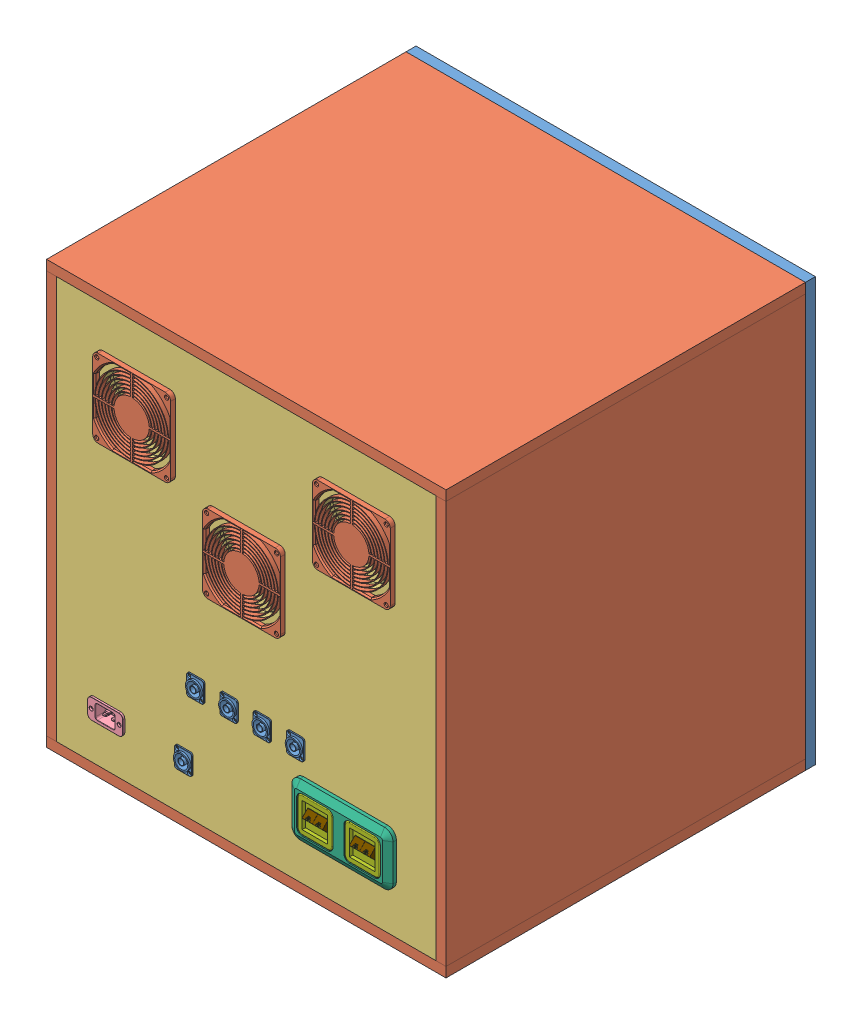
SolidWorks assembly Verlängerung, configuration Standard. Lengths in mm.
Overall size (600 635 570.02).
74 component instances, 21 part files, 63 mates.
Components (placement in the parent):
- Lochplatte-1: Lochplatte [Standard] at (-600 0 0) size (600 635 15)
- Platten-1: Platten [Standard] at (-600 620 555) x (1 0 0) z (0 1 0) size (600 540 15)
- Platten-2: Platten [Standard] at (-600 0 555) x (1 0 0) z (0 1 0) size (600 540 15)
- Platten-3: Platten [seite] at (-585 15 555) x (0 1 0) z (-1 0 0) size (605 540 15)
- Platten-4: Platten [seite] at (0 15 555) x (0 1 0) z (-1 0 0) size (605 540 15)
- Back-1: Back [Standard] at (-585 15 540) size (570 605 15)
- 17322-1: 17322 [Default] at (-509 87 555) size (53 30 30)
- Hohlwanddose-1: Hohlwanddose [Standard] at (-186 115 556) x (0 0 -1) z (1 0 0) size (60.7 71 71)
- Hohlwanddose-2: Hohlwanddose [Standard] at (-115 115 556) x (0 0 -1) z (1 0 0) size (60.7 71 71)
- Steckdose_2er-RJ45-1: Steckdose_2er-RJ45 [Standard] at (-243.8004 7.3351 555.8552) size (152 80 25.23)
  - Wandplatte-1: Wandplatte [2er] at (17.3004 67.6649 10.1448) size (152 80 11)
  - Steckdose-RJ45-1: Steckdose-RJ45 [Standard] at (177.7047 18.6812 -53.8826) x (0 -1 0) z (0 0 1) size (54 54 25.23)
    - Buchse-RJ45-1: Buchse-RJ45 [Standard] at (-88.9836 -48.9043 64.0274) size (54 54 6.5)
    - 65864-1: 65864 [Default] at (-88.8386 -41.2043 53.1274) size (17.49 15.42 25.23)
      - 65864_01-1: 65864_01 [Default] at origin size (9.69 0.75 13.83)
      - 65864_02-1: 65864_02 [Default] at origin size (9.44 0.68 13.83)
      - 65864_03-1: 65864_03 [Default] at origin size (9.69 0.61 13.84)
      - 65864_04-1: 65864_04 [Default] at origin size (9.44 0.54 13.83)
      - 65864_05-1: 65864_05 [Default] at origin size (9.69 0.54 13.82)
      - 65864_06-1: 65864_06 [Default] at origin size (9.44 0.6 13.83)
      - 65864_07-1: 65864_07 [Default] at origin size (9.69 0.68 13.83)
      - 65864_08-1: 65864_08 [Default] at origin size (9.44 0.75 13.83)
      - 65864_09-1: 65864_09 [Default] at origin size (17.11 15.1 23.65)
      - 65864_10-1: 65864_10 [Default] at origin size (6.36 10.31 6.36)
      - 65864_11-1: 65864_11 [Default] at origin size (17.49 15.42 25.23)
    - 65864-2: 65864 [Default] at (-88.8386 -56.6043 53.1274) size (17.49 15.42 25.23)
      - 65864_01-1: 65864_01 [Default] at origin size (9.69 0.75 13.83)
      - 65864_02-1: 65864_02 [Default] at origin size (9.44 0.68 13.83)
      - 65864_03-1: 65864_03 [Default] at origin size (9.69 0.61 13.84)
      - 65864_04-1: 65864_04 [Default] at origin size (9.44 0.54 13.83)
      - 65864_05-1: 65864_05 [Default] at origin size (9.69 0.54 13.82)
      - 65864_06-1: 65864_06 [Default] at origin size (9.44 0.6 13.83)
      - 65864_07-1: 65864_07 [Default] at origin size (9.69 0.68 13.83)
      - 65864_08-1: 65864_08 [Default] at origin size (9.44 0.75 13.83)
      - 65864_09-1: 65864_09 [Default] at origin size (17.11 15.1 23.65)
      - 65864_10-1: 65864_10 [Default] at origin size (6.36 10.31 6.36)
      - 65864_11-1: 65864_11 [Default] at origin size (17.49 15.42 25.23)
  - Steckdose-RJ45-2: Steckdose-RJ45 [Standard] at (106.7047 18.6812 -53.8826) x (0 -1 0) z (0 0 1) size (54 54 25.23)
    - Buchse-RJ45-1: Buchse-RJ45 [Standard] at (-88.9836 -48.9043 64.0274) size (54 54 6.5)
    - 65864-1: 65864 [Default] at (-88.8386 -41.2043 53.1274) size (17.49 15.42 25.23)
      - 65864_01-1: 65864_01 [Default] at origin size (9.69 0.75 13.83)
      - 65864_02-1: 65864_02 [Default] at origin size (9.44 0.68 13.83)
      - 65864_03-1: 65864_03 [Default] at origin size (9.69 0.61 13.84)
      - 65864_04-1: 65864_04 [Default] at origin size (9.44 0.54 13.83)
      - 65864_05-1: 65864_05 [Default] at origin size (9.69 0.54 13.82)
      - 65864_06-1: 65864_06 [Default] at origin size (9.44 0.6 13.83)
      - 65864_07-1: 65864_07 [Default] at origin size (9.69 0.68 13.83)
      - 65864_08-1: 65864_08 [Default] at origin size (9.44 0.75 13.83)
      - 65864_09-1: 65864_09 [Default] at origin size (17.11 15.1 23.65)
      - 65864_10-1: 65864_10 [Default] at origin size (6.36 10.31 6.36)
      - 65864_11-1: 65864_11 [Default] at origin size (17.49 15.42 25.23)
    - 65864-2: 65864 [Default] at (-88.8386 -56.6043 53.1274) size (17.49 15.42 25.23)
      - 65864_01-1: 65864_01 [Default] at origin size (9.69 0.75 13.83)
      - 65864_02-1: 65864_02 [Default] at origin size (9.44 0.68 13.83)
      - 65864_03-1: 65864_03 [Default] at origin size (9.69 0.61 13.84)
      - 65864_04-1: 65864_04 [Default] at origin size (9.44 0.54 13.83)
      - 65864_05-1: 65864_05 [Default] at origin size (9.69 0.54 13.82)
      - 65864_06-1: 65864_06 [Default] at origin size (9.44 0.6 13.83)
      - 65864_07-1: 65864_07 [Default] at origin size (9.69 0.68 13.83)
      - 65864_08-1: 65864_08 [Default] at origin size (9.44 0.75 13.83)
      - 65864_09-1: 65864_09 [Default] at origin size (17.11 15.1 23.65)
      - 65864_10-1: 65864_10 [Default] at origin size (6.36 10.31 6.36)
      - 65864_11-1: 65864_11 [Default] at origin size (17.49 15.42 25.23)
- NBB75DFG-1: NBB75DFG [Standard] at (-393 87 555) x (-1 0 0) z (0 0 -1) size (26 31 34)
- NBB75DFG-2: NBB75DFG [Standard] at (-375 190 555) x (-1 0 0) z (0 0 -1) size (26 31 34)
- NBB75DFG-3: NBB75DFG [Standard] at (-325 190 555) x (-1 0 0) z (0 0 -1) size (26 31 34)
- NBB75DFG-4: NBB75DFG [Standard] at (-275 190 555) x (-1 0 0) z (0 0 -1) size (26 31 34)
- NBB75DFG-5: NBB75DFG [Standard] at (-225 190 555) x (-1 0 0) z (0 0 -1) size (26 31 34)
- Schutz-2: Schutz [Standard] at (-135 500 555) size (117 117 7.2)
- Schutz-3: Schutz [Standard] at (-300 380 555) size (117 117 7.2)
- 46362-1: 46362 [Default] at (-135 500 540) x (-1 0 0) z (0 0 -1) size (119.05 119.01 25.4)
- 46362-2: 46362 [Default] at (-465 500 540) x (-1 0 0) z (0 0 -1) size (119.05 119.01 25.4)
- 46362-3: 46362 [Default] at (-300 380 540) x (-1 0 0) z (0 0 -1) size (119.05 119.01 25.4)
- Schutz-1: Schutz [Standard] at (-465 500 555) size (117 117 7.2)
Mates (geometry in assembly coordinates):
- Deckungsgleich1: coincident anti-aligned: plane of Lochplatte-1 through (-600 0 15) normal (0 0 1); plane of Platten-1 through (-600 635 15) normal (0 0 -1)
- Deckungsgleich2: coincident aligned: plane of Lochplatte-1 through (0 0 15) normal (1 0 0); plane of Platten-1 through (0 635 15) normal (1 0 0)
- Deckungsgleich3: coincident aligned: plane of Lochplatte-1 through (-600 635 15) normal (0 1 0); plane of Platten-1 through (-600 635 555) normal (0 1 0)
- Deckungsgleich4: coincident anti-aligned: plane of Lochplatte-1 through (-600 0 15) normal (0 0 1); plane of Platten-2 through (-600 15 15) normal (0 0 -1)
- Deckungsgleich5: coincident aligned: plane of Lochplatte-1 through (-600 0 15) normal (-1 0 0); plane of Platten-2 through (-600 15 15) normal (-1 0 0)
- Deckungsgleich6: coincident aligned: plane of Lochplatte-1 through (-600 0 15) normal (0 -1 0); plane of Platten-2 through (-600 0 555) normal (0 -1 0)
- Deckungsgleich7: coincident anti-aligned: plane of Lochplatte-1 through (-600 0 15) normal (0 0 1); plane of Platten-3 through (-600 15 15) normal (0 0 -1)
- Deckungsgleich8: coincident aligned: plane of Lochplatte-1 through (-600 0 15) normal (-1 0 0); plane of Platten-3 through (-600 15 555) normal (-1 0 0)
- Deckungsgleich9: coincident anti-aligned: plane of Platten-1 through (-600 620 555) normal (0 -1 0); plane of Platten-3 through (-600 620 15) normal (0 1 0)
- Deckungsgleich10: coincident anti-aligned: plane of Lochplatte-1 through (-600 0 15) normal (0 0 1); plane of Platten-4 through (-15 15 15) normal (0 0 -1)
- Deckungsgleich11: coincident anti-aligned: plane of Platten-1 through (-600 620 555) normal (0 -1 0); plane of Platten-4 through (-15 620 15) normal (0 1 0)
- Deckungsgleich12: coincident aligned: plane of Lochplatte-1 through (0 0 15) normal (1 0 0); plane of Platten-4 through (0 15 555) normal (1 0 0)
- Deckungsgleich13: coincident anti-aligned: plane of Platten-1 through (-600 620 555) normal (0 -1 0); plane of Back-1 through (-585 620 555) normal (0 1 0)
- Deckungsgleich14: coincident anti-aligned: plane of Platten-3 through (-585 15 555) normal (1 0 0); plane of Back-1 through (-585 15 555) normal (-1 0 0)
- Deckungsgleich15: coincident aligned: plane of Platten-1 through (-600 635 555) normal (0 0 1); plane of Back-1 through (-585 15 555) normal (0 0 1)
- Deckungsgleich18: coincident anti-aligned: plane of Back-1 through (-493 99 535) normal (-1 0 0); plane of 17322-1 through (-493 79.1 537) normal (1 0 0)
- Deckungsgleich19: coincident anti-aligned: plane of Back-1 through (-525 99 535) normal (0 -1 0); plane of 17322-1 through (-497.1 99 537) normal (0 1 0)
- Deckungsgleich20: coincident anti-aligned: plane of Back-1 through (-585 15 555) normal (0 0 1); plane of 17322-1 through (-529.5 78 555) normal (0 0 -1)
- Konzentrisch2: concentric aligned: cylinder of Back-1 through (-186 115 535) axis (0 0 1) radius 34; cylinder of Hohlwanddose-1 through (-186 115 529.5) axis (0 0 1) radius 33.5
- Konzentrisch3: concentric aligned: cylinder of Back-1 through (-115 115 535) axis (0 0 1) radius 34; cylinder of Hohlwanddose-2 through (-115 115 529.5) axis (0 0 1) radius 33.5
- Parallel2: parallel aligned: plane of Platten-4 through (0 15 555) normal (1 0 0); plane of Hohlwanddose-2 through (-141.9807 109 528) normal (1 0 0)
- Parallel3: parallel aligned: plane of Hohlwanddose-1 through (-212.9807 109 528) normal (1 0 0); plane of Hohlwanddose-2 through (-141.9807 109 528) normal (1 0 0)
- Deckungsgleich23: coincident anti-aligned: plane of Back-1 through (-585 15 555) normal (0 0 1); plane of Hohlwanddose-2 through (-115 149.5 555) normal (0 0 -1)
- Deckungsgleich24: coincident anti-aligned: plane of Back-1 through (-585 15 555) normal (0 0 1); plane of Hohlwanddose-1 through (-186 149.5 555) normal (0 0 -1)
- Konzentrisch4: concentric anti-aligned: cylinder of Hohlwanddose-2 through (-115 115 529.5) axis (0 0 1) radius 32.5; circle of Steckdose_2er-RJ45-1/Steckdose-RJ45-1/Buchse-RJ45-1
- Konzentrisch5: concentric anti-aligned: cylinder of Hohlwanddose-1 through (-186 115 529.5) axis (0 0 1) radius 32.5; circle of Steckdose_2er-RJ45-1/Steckdose-RJ45-2/Buchse-RJ45-1
- Deckungsgleich25: coincident anti-aligned: plane of Back-1 through (-585 15 555) normal (0 0 1); plane of Steckdose_2er-RJ45-1/Wandplatte-1 through (-213.7 87.8 555) normal (0 0 -1)
- Deckungsgleich26: coincident aligned: plane of Lochplatte-1 through (0 0 15) normal (1 0 0); plane of assembly through (0 0 0) normal (1 0 0)
- Deckungsgleich27: coincident anti-aligned: plane of Lochplatte-1 through (-600 0 15) normal (0 -1 0); plane of assembly through (0 0 0) normal (0 1 0)
- Deckungsgleich28: coincident anti-aligned: plane of Lochplatte-1 through (-600 0 0) normal (0 0 -1); plane of assembly through (0 0 0) normal (0 0 1)
- Deckungsgleich29: coincident anti-aligned: plane of Back-1 through (-585 15 555) normal (0 0 1); plane of Schutz-1 through (-515.5 449.5 555) normal (0 0 -1)
- Deckungsgleich30: coincident anti-aligned: plane of Back-1 through (-585 15 555) normal (0 0 1); plane of Schutz-3 through (-350.5 329.5 555) normal (0 0 -1)
- Deckungsgleich31: coincident anti-aligned: plane of Back-1 through (-585 15 555) normal (0 0 1); plane of Schutz-2 through (-185.5 449.5 555) normal (0 0 -1)
- Konzentrisch6: concentric anti-aligned: cylinder of Back-1 through (-517.4 552.4 535) axis (0 0 1) radius 2; cylinder of Schutz-1 through (-517.4 552.4 562.2) axis (0 0 -1) radius 2.15
- Konzentrisch7: concentric anti-aligned: cylinder of Back-1 through (-412.6 447.6 535) axis (0 0 1) radius 2; cylinder of Schutz-1 through (-412.6 447.6 562.2) axis (0 0 -1) radius 2.15
- Konzentrisch8: concentric anti-aligned: cylinder of Back-1 through (-352.4 432.4 535) axis (0 0 1) radius 2; cylinder of Schutz-3 through (-352.4 432.4 562.2) axis (0 0 -1) radius 2.15
- Konzentrisch9: concentric anti-aligned: cylinder of Back-1 through (-247.6 327.6 535) axis (0 0 1) radius 2; cylinder of Schutz-3 through (-247.6 327.6 562.2) axis (0 0 -1) radius 2.15
- Konzentrisch10: concentric anti-aligned: cylinder of Back-1 through (-187.4 552.4 535) axis (0 0 1) radius 2; cylinder of Schutz-2 through (-187.4 552.4 562.2) axis (0 0 -1) radius 2.15
- Konzentrisch11: concentric anti-aligned: cylinder of Back-1 through (-82.6 447.6 535) axis (0 0 1) radius 2; cylinder of Schutz-2 through (-82.6 447.6 562.2) axis (0 0 -1) radius 2.15
- Deckungsgleich32: coincident anti-aligned: plane of Back-1 through (-585 15 540) normal (0 0 -1); plane of 46362-1 through (-135 500 540) normal (0 0 1)
- Deckungsgleich33: coincident anti-aligned: plane of Back-1 through (-585 15 540) normal (0 0 -1); plane of 46362-2 through (-465 500 540) normal (0 0 1)
- Deckungsgleich34: coincident anti-aligned: plane of Back-1 through (-585 15 540) normal (0 0 -1); plane of 46362-3 through (-300 380 540) normal (0 0 1)
- Konzentrisch12: concentric anti-aligned: cylinder of Back-1 through (-135 500 535) axis (0 0 1) radius 55.5; cylinder of 46362-1 through (-135 500 540) axis (0 0 -1) radius 58.5
- Konzentrisch13: concentric anti-aligned: cylinder of Back-1 through (-465 500 535) axis (0 0 1) radius 55.5; cylinder of 46362-2 through (-465 500 540) axis (0 0 -1) radius 58.5
- Konzentrisch14: concentric anti-aligned: cylinder of Back-1 through (-300 380 535) axis (0 0 1) radius 55.5; cylinder of 46362-3 through (-300 380 540) axis (0 0 -1) radius 58.5
- Parallel4: parallel anti-aligned: plane of Platten-1 through (-600 620 555) normal (0 -1 0); plane of 46362-1 through (-192.5 559.5 540) normal (0 1 0)
- Parallel5: parallel anti-aligned: plane of Platten-1 through (-600 620 555) normal (0 -1 0); plane of 46362-2 through (-522.5 559.5 540) normal (0 1 0)
- Parallel6: parallel anti-aligned: plane of Platten-1 through (-600 620 555) normal (0 -1 0); plane of 46362-3 through (-357.5 439.5 540) normal (0 1 0)
- Deckungsgleich35: coincident anti-aligned: plane of Back-1 through (-585 15 555) normal (0 0 1); plane of NBB75DFG-1 through (-393 87 555) normal (0 0 -1)
- Deckungsgleich37: coincident anti-aligned: plane of Back-1 through (-585 15 555) normal (0 0 1); plane of NBB75DFG-2 through (-375 190 555) normal (0 0 -1)
- Deckungsgleich38: coincident anti-aligned: plane of Back-1 through (-585 15 555) normal (0 0 1); plane of NBB75DFG-3 through (-325 190 555) normal (0 0 -1)
- Deckungsgleich39: coincident anti-aligned: plane of Back-1 through (-585 15 555) normal (0 0 1); plane of NBB75DFG-4 through (-275 190 555) normal (0 0 -1)
- Deckungsgleich40: coincident anti-aligned: plane of Back-1 through (-585 15 555) normal (0 0 1); plane of NBB75DFG-5 through (-225 190 555) normal (0 0 -1)
- Konzentrisch15: concentric aligned: cylinder of Back-1 through (-393 87 535) axis (0 0 1) radius 11.5; cylinder of NBB75DFG-1 through (-393 87 524.4) axis (0 0 1) radius 11
- Konzentrisch16: concentric aligned: cylinder of Back-1 through (-375 190 535) axis (0 0 1) radius 11.5; cylinder of NBB75DFG-2 through (-375 190 524.4) axis (0 0 1) radius 11
- Konzentrisch17: concentric aligned: cylinder of Back-1 through (-325 190 535) axis (0 0 1) radius 11.5; cylinder of NBB75DFG-3 through (-325 190 524.4) axis (0 0 1) radius 11
- Konzentrisch18: concentric aligned: cylinder of Back-1 through (-275 190 535) axis (0 0 1) radius 11.5; cylinder of NBB75DFG-4 through (-275 190 524.4) axis (0 0 1) radius 11
- Konzentrisch19: concentric aligned: cylinder of Back-1 through (-225 190 535) axis (0 0 1) radius 11.5; cylinder of NBB75DFG-5 through (-225 190 524.4) axis (0 0 1) radius 11
- Parallel7: parallel: line of Platten-2 through (-600 15 555) axis (1 0 0); plane of NBB75DFG-1 through (-402.5 71.5 555) normal (0 -1 0)
- Parallel8: parallel: line of Platten-2 through (-600 15 555) axis (1 0 0); plane of NBB75DFG-2 through (-384.5 174.5 555) normal (0 -1 0)
- Parallel9: parallel: line of Platten-2 through (-600 15 555) axis (1 0 0); plane of NBB75DFG-3 through (-334.5 174.5 555) normal (0 -1 0)
- Parallel10: parallel: line of Platten-2 through (-600 15 555) axis (1 0 0); plane of NBB75DFG-4 through (-284.5 174.5 555) normal (0 -1 0)
- Parallel11: parallel: line of Platten-2 through (-600 15 555) axis (1 0 0); plane of NBB75DFG-5 through (-234.5 174.5 555) normal (0 -1 0)
